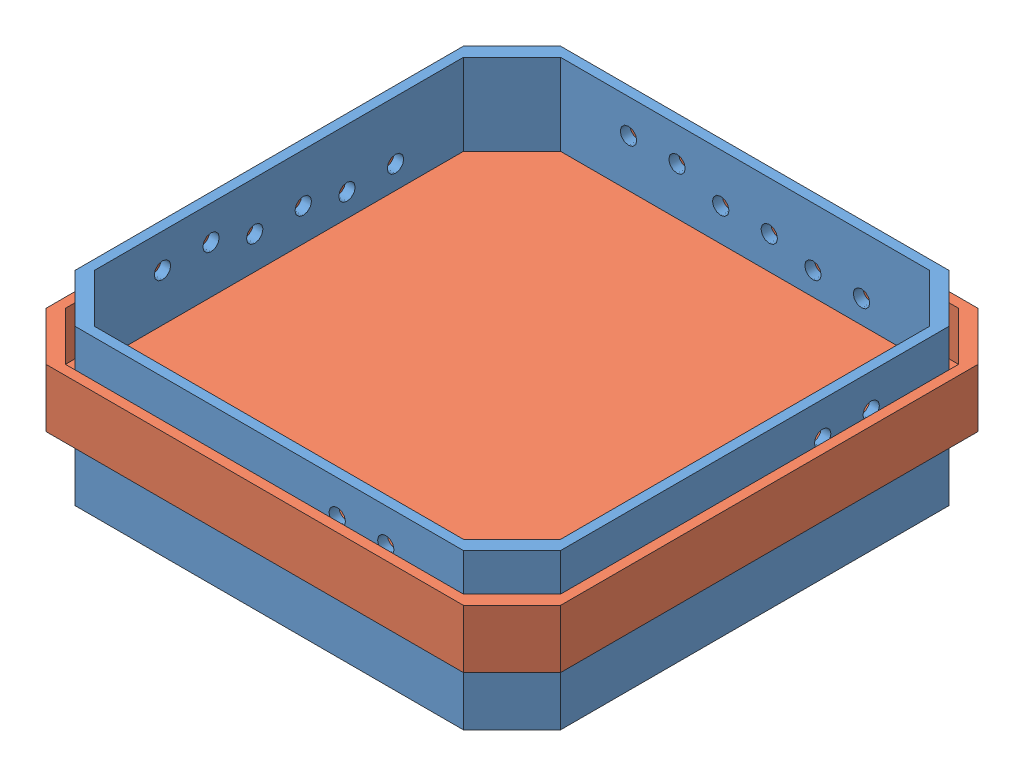
SolidWorks assembly Assem1, configuration Default. Lengths in mm.
Overall size (106 32 106).
2 component instances, 2 part files, 2 mates.
Components (placement in the parent):
- bottom-1: bottom [Default] at (36.7238 38.5258 78.884) size (100 32 100)
- top-1: top [Default] at (36.7238 51.7482 78.884) size (106 12 106)
Mates (geometry in assembly coordinates):
- Coincident2: coincident aligned: plane of bottom-1 through (36.7238 38.5258 78.884) normal (0 0 1); plane of top-1 through (36.7238 51.7482 78.884) normal (0 0 1)
- Coincident4: coincident aligned: plane of bottom-1 through (36.7238 38.5258 78.884) normal (1 0 0); plane of top-1 through (36.7238 51.7482 78.884) normal (1 0 0)
